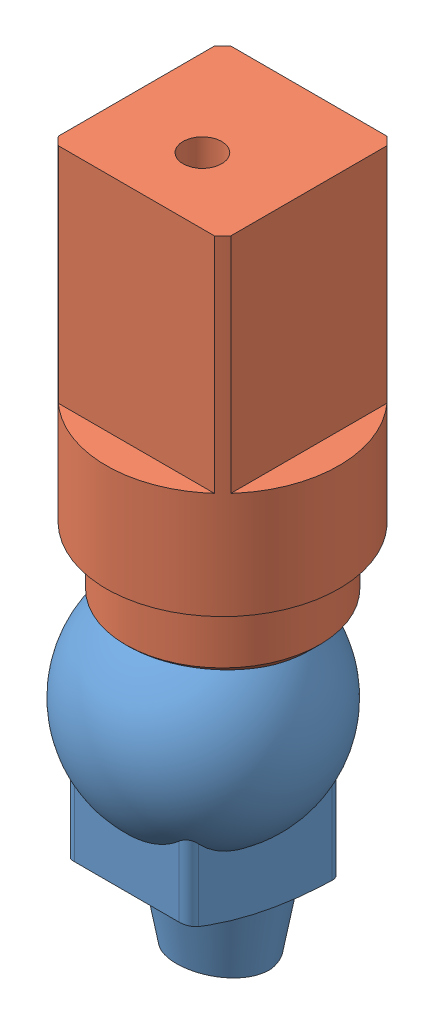
SolidWorks assembly Szelepbetétkar, configuration Default. Lengths in mm.
Overall size (12 36.14 12.7).
2 component instances, 2 part files, 6 mates.
Components (placement in the parent):
- Szelepbetétkar_alsó-1: Szelepbetétkar_alsó [Default] at origin size (11.4 30.14 11.4)
- Szelepbetétkar_felső-1: Szelepbetétkar_felső [Default] at (0 7.3478 -1) size (12 20.79 12)
Mates (geometry in assembly coordinates):
- Coincident1: coincident aligned: plane of Szelepbetétkar_alsó-1 through (0 0 0) normal (0 0 1)
- Coincident2: coincident aligned: plane of Szelepbetétkar_alsó-1 through (0 0 0) normal (0 1 0)
- Coincident3: coincident aligned: plane of Szelepbetétkar_alsó-1 through (0 0 0) normal (1 0 0)
- Distance1: distance = 1 mm aligned: plane of Szelepbetétkar_felső-1 through (0 7.3478 -1) normal (0 0 1)
- Coincident4: coincident aligned: plane of Szelepbetétkar_alsó-1 through (0 0 0) normal (1 0 0); plane of Szelepbetétkar_felső-1 through (0 7.3478 -1) normal (1 0 0)
- Distance2: distance = 36 mm anti-aligned: plane of Szelepbetétkar_alsó-1 through (0 -11.6522 0) normal (0 -1 0); plane of Szelepbetétkar_felső-1 through (0 24.3478 -1) normal (0 1 0)
